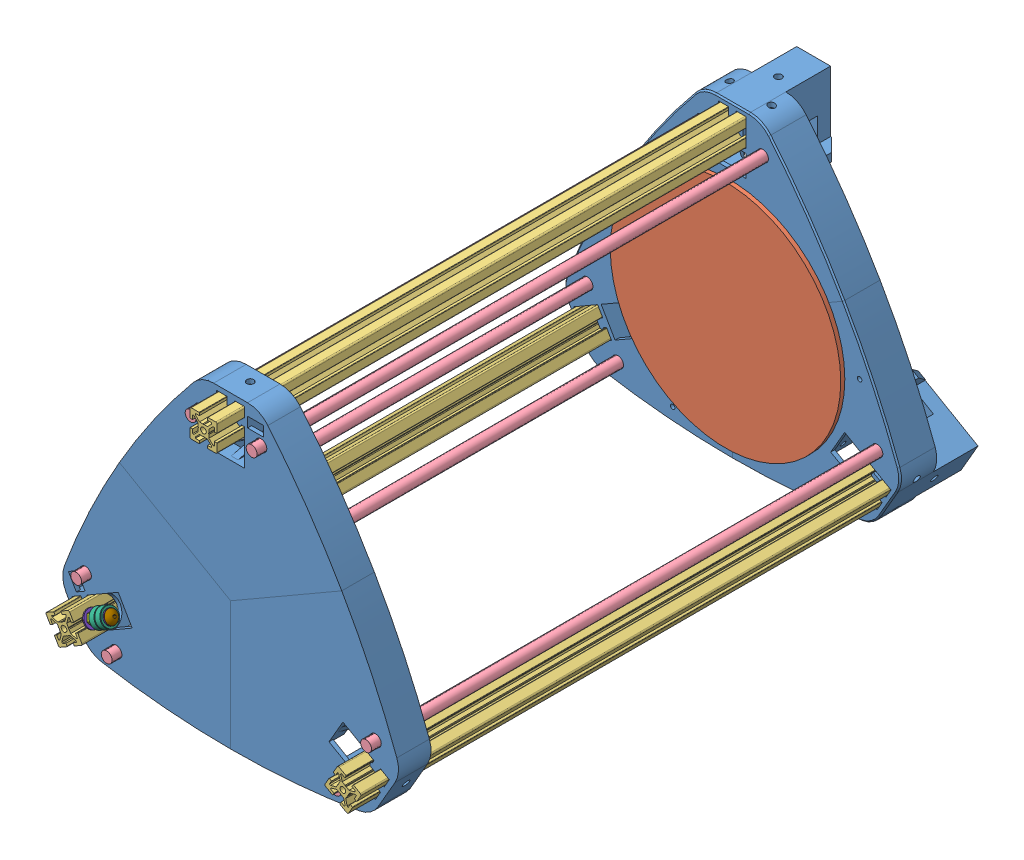
SolidWorks assembly 3DR Delta Printer, configuration Default. Lengths in mm.
Overall size (311.93 270.14 450).
32 component instances, 12 part files, 51 mates.
Components (placement in the parent):
- 3DR Bottom Motor Mount-1: 3DR Bottom Motor Mount [Default] at (103.057 -59.5 116.8875) x (-0.5 -0.866025 0) z (0 0 -1) size (164 132.75 60)
- 3DR Bottom Motor Mount-2: 3DR Bottom Motor Mount [Default] at (-103.057 -59.5 116.8875) x (-0.5 0.866025 0) z (0 0 -1) size (164 132.75 60)
- 3DR Bottom Motor Mount-3: 3DR Bottom Motor Mount [Default] at (0 119 116.8875) x (1 0 0) z (0 0 -1) size (164 132.75 60)
- Round Plate-1: Round Plate [Default] at (0 0 118.8875) size (170 170 3)
- HFSB5-2020-450-1: HFSB5-2020-450 [Default] at (102.8405 -59.375 506.8875) x (0.5 0.866025 0) z (0 0 1) size (20 20 450)
- HFSB5-2020-450-2: HFSB5-2020-450 [Default] at (0 118.75 506.8875) x (0 -1 0) z (0 0 1) size (20 20 450)
- HFSB5-2020-450-3: HFSB5-2020-450 [Default] at (-102.8405 -59.375 506.8875) x (-0.866025 -0.5 0) z (0 0 1) size (20 20 450)
- RGOCG8-400-1: RGOCG8-400 [Default] at (-84.4025 -74.7106 93.8875) x (-0.528567 -0.848892 0) z (0 0 1) size (8 8 400)
- RGOCG8-400-2: RGOCG8-400 [Default] at (-106.9025 -35.7394 93.8875) size (8 8 400)
- RGOCG8-400-3: RGOCG8-400 [Default] at (84.4025 -74.7106 93.8875) size (8 8 400)
- RGOCG8-400-4: RGOCG8-400 [Default] at (106.9025 -35.7394 93.8875) size (8 8 400)
- RGOCG8-400-5: RGOCG8-400 [Default] at (22.5 110.45 93.8875) size (8 8 400)
- RGOCG8-400-6: RGOCG8-400 [Default] at (-22.5 110.45 93.8875) size (8 8 400)
- 3DR_Spool_V2_001_RTP-1: 3DR_Spool_V2_001_RTP [Default] at (-97.0822 -43.3487 98.8875) x (0.5 -0.866025 0) z (0.866025 0.5 0) size (22 22 23) (hidden)
- Thread-1: Thread [Default] at (-87.4762 -40.1121 344.3217) x (0.866025 0.5 0) z (0 0 1) size (0.5 0.5 400) (hidden)
- Carriage for LM8UU-1: Carriage for LM8UU [Default] at (-93.0343 -53.7134 364.8923) x (-0.5 0.866025 0) z (0 0 -1) size (65.8 24.09 24)
- 3DR Bottom Motor Mount-4: 3DR Bottom Motor Mount [Top] at (-103.057 -59.5 486.8875) x (-0.5 0.866025 0) z (0 0 -1) size (164 132.75 25.42)
- 3DR Bottom Motor Mount-5: 3DR Bottom Motor Mount [Top] at (103.057 -59.5 486.8875) x (-0.5 -0.866025 0) z (0 0 -1) size (164 132.75 25.42)
- 3DR Bottom Motor Mount-6: 3DR Bottom Motor Mount [Top] at (0 119 486.8875) x (1 0 0) z (0 0 -1) size (164 132.75 25.42)
- Spectra Idler-1: Spectra Idler [Default] at (-89.2006 -51.5 495.0971) x (0 0 -1) z (0.866025 0.5 0) size (15.69 15.69 24.76)
  - 624ZZ-1: 624ZZ [Default] at origin size (13 13 5)
  - 624ZZ-2: 624ZZ [Default] at (0 0 5) size (13 13 5)
  - Nut-1: Nut [M5] at (0 0 -4.75) size (9.12 7.9 3.75)
  - Washer-1: Washer [M5] at (0 0 10) size (9.75 9.75 1)
  - Washer-2: Washer [M5] at (0 0 -1) size (9.75 9.75 1)
  - Washer-3: Washer [M5 Fender] at (0 0 -5.75) x (0.384822 -0.922991 0) z (0 0 1) size (12 12 1)
  - Button Head Screw-1: Button Head Screw [M5 x 22] at (0 0 -11) size (9.5 9.5 24.76)
- Spool and Screws-1: Spool and Screws [Default] at (-93.3142 -53.875 87.8875) x (0.136756 -0.236868 0.961869) z (0.866025 0.5 0) size (21.5 23.26 23)
  - Spool-1: Spool [Default] at origin size (21.5 23.26 23)
  - Button Head Screw-1: Button Head Screw [M3 x 6] at (-1.5 0 19.9458) x (0 0 1) z (-1 0 0) size (5.4 5.4 7.92)
  - Button Head Screw-2: Button Head Screw [M3 x 6] at (0.75 -1.299 19.9458) x (0 0 1) z (0.5 -0.866025 0) size (5.4 5.4 7.92)
  - Button Head Screw-3: Button Head Screw [M3 x 6] at (0.75 1.299 19.9458) x (0 0 1) z (0.5 0.866025 0) size (5.4 5.4 7.92)
Mates (geometry in assembly coordinates):
- Coincident10: coincident aligned: plane of Round Plate-1 through (0 0 118.8875) normal (0 1 0); plane of assembly through (0 0 0) normal (0 1 0)
- Coincident11: coincident aligned: plane of Round Plate-1 through (0 0 118.8875) normal (1 0 0); plane of assembly through (0 0 0) normal (1 0 0)
- Distance1: distance = 2 mm anti-aligned: plane of Round Plate-1 through (0 0 118.8875) normal (0 0 -1); plane of 3DR Bottom Motor Mount-3 through (-12.5 132.75 116.8875) normal (0 0 1)
- Coincident12: coincident anti-aligned: plane of 3DR Bottom Motor Mount-1 through (99.3053 -45.4982 56.8875) normal (0.866025 -0.5 0); plane of HFSB5-2020-450-1 through (98.6803 -46.5808 56.8875) normal (-0.866025 0.5 0)
- Width1: width anti-aligned: plane of HFSB5-2020-450-1 through (104.9826 -49.0647 56.8875) normal (0.5 0.866025 0); plane of HFSB5-2020-450-1 through (90.0463 -63.5353 56.8875) normal (-0.5 -0.866025 0); plane of 3DR Bottom Motor Mount-1 through (117.0588 -55.7482 56.8875) normal (-0.5 -0.866025 0); plane of 3DR Bottom Motor Mount-1 through (106.8088 -73.5018 56.8875) normal (0.5 0.866025 0)
- Coincident14: coincident aligned: plane of 3DR Bottom Motor Mount-1 through (121.2149 -55.5497 56.8875) normal (0 0 -1); plane of HFSB5-2020-450-1 through (90.5463 -62.6692 56.8875) normal (0 0 -1)
- Coincident15: coincident anti-aligned: plane of 3DR Bottom Motor Mount-3 through (-10.25 108.75 56.8875) normal (0 1 0); plane of HFSB5-2020-450-2 through (-9 108.75 56.8875) normal (0 -1 0)
- Width2: width anti-aligned: plane of 3DR Bottom Motor Mount-3 through (-10.25 129.25 56.8875) normal (1 0 0); plane of 3DR Bottom Motor Mount-3 through (10.25 129.25 56.8875) normal (-1 0 0); plane of HFSB5-2020-450-2 through (-10 115.45 56.8875) normal (-1 0 0); plane of HFSB5-2020-450-2 through (10 109.75 56.8875) normal (1 0 0)
- Coincident16: coincident aligned: plane of 3DR Bottom Motor Mount-3 through (-12.5 132.75 56.8875) normal (0 0 -1); plane of HFSB5-2020-450-2 through (9 127.75 56.8875) normal (0 0 -1)
- Coincident17: coincident anti-aligned: plane of 3DR Bottom Motor Mount-2 through (-89.0553 -63.2518 56.8875) normal (-0.866025 -0.5 0); plane of HFSB5-2020-450-3 through (-89.6803 -62.1692 56.8875) normal (0.866025 0.5 0)
- Width3: width anti-aligned: plane of 3DR Bottom Motor Mount-2 through (-106.8088 -73.5018 56.8875) normal (-0.5 0.866025 0); plane of 3DR Bottom Motor Mount-2 through (-117.0588 -55.7482 56.8875) normal (0.5 -0.866025 0); plane of HFSB5-2020-450-3 through (-94.9826 -66.3853 56.8875) normal (0.5 -0.866025 0); plane of HFSB5-2020-450-3 through (-100.0463 -46.2147 56.8875) normal (-0.5 0.866025 0)
- Coincident18: coincident aligned: plane of 3DR Bottom Motor Mount-2 through (-108.7149 -77.2003 56.8875) normal (0 0 -1); plane of HFSB5-2020-450-3 through (-90.5463 -62.6692 56.8875) normal (0 0 -1)
- Concentric1: concentric anti-aligned: cylinder of 3DR Bottom Motor Mount-2 through (-84.4025 -74.7106 93.8875) axis (0 0 1) radius 4.15; cylinder of RGOCG8-400-1 through (-84.4025 -74.7106 493.8875) axis (0 0 -1) radius 4
- Coincident19: coincident anti-aligned: plane of 3DR Bottom Motor Mount-2 through (-84.4025 -74.7106 93.8875) normal (0 0 1); plane of RGOCG8-400-1 through (-84.4025 -74.7106 93.8875) normal (0 0 -1)
- Coincident20: coincident aligned: plane of RGOCG8-400-1 through (-84.4025 -74.7106 93.8875) normal (0 0 1); plane of RGOCG8-400-2 through (-106.9025 -35.7394 93.8875) normal (0 0 1)
- Concentric2: concentric anti-aligned: cylinder of 3DR Bottom Motor Mount-2 through (-106.9025 -35.7394 93.8875) axis (0 0 1) radius 4.15; cylinder of RGOCG8-400-2 through (-106.9025 -35.7394 493.8875) axis (0 0 -1) radius 4
- Coincident21: coincident aligned: plane of RGOCG8-400-1 through (-84.4025 -74.7106 93.8875) normal (0 0 1); plane of RGOCG8-400-3 through (84.4025 -74.7106 93.8875) normal (0 0 1)
- Concentric3: concentric anti-aligned: cylinder of 3DR Bottom Motor Mount-1 through (84.4025 -74.7106 93.8875) axis (0 0 1) radius 4.15; cylinder of RGOCG8-400-3 through (84.4025 -74.7106 493.8875) axis (0 0 -1) radius 4
- Coincident22: coincident aligned: plane of RGOCG8-400-1 through (-84.4025 -74.7106 93.8875) normal (0 0 1); plane of RGOCG8-400-4 through (106.9025 -35.7394 93.8875) normal (0 0 1)
- Concentric4: concentric anti-aligned: cylinder of 3DR Bottom Motor Mount-1 through (106.9025 -35.7394 93.8875) axis (0 0 1) radius 4.15; cylinder of RGOCG8-400-4 through (106.9025 -35.7394 493.8875) axis (0 0 -1) radius 4
- Coincident23: coincident aligned: plane of RGOCG8-400-1 through (-84.4025 -74.7106 93.8875) normal (0 0 1); plane of RGOCG8-400-5 through (22.5 110.45 93.8875) normal (0 0 1)
- Concentric5: concentric anti-aligned: cylinder of 3DR Bottom Motor Mount-3 through (22.5 110.45 93.8875) axis (0 0 1) radius 4.15; cylinder of RGOCG8-400-5 through (22.5 110.45 493.8875) axis (0 0 -1) radius 4
- Coincident24: coincident aligned: plane of RGOCG8-400-1 through (-84.4025 -74.7106 93.8875) normal (0 0 1); plane of RGOCG8-400-6 through (-22.5 110.45 93.8875) normal (0 0 1)
- Concentric6: concentric anti-aligned: cylinder of 3DR Bottom Motor Mount-3 through (-22.5 110.45 93.8875) axis (0 0 1) radius 4.15; cylinder of RGOCG8-400-6 through (-22.5 110.45 493.8875) axis (0 0 -1) radius 4
- Concentric7: concentric aligned: cylinder of 3DR Bottom Motor Mount-2 through (-113.2434 -65.3811 87.8875) axis (0.866025 0.5 0) radius 14.5; line of 3DR_Spool_V2_001_RTP-1 through (-161.6436 -93.325 87.8875) axis (0.866025 0.5 0)
- Distance2: distance = 24 mm aligned: plane of 3DR_Spool_V2_001_RTP-1 through (-97.0822 -43.3487 98.8875) normal (0.866025 0.5 0); plane of 3DR Bottom Motor Mount-2 through (-59.2976 -60.7936 116.8875) normal (0.866025 0.5 0)
- Parallel1: parallel anti-aligned: plane of 3DR_Spool_V2_001_RTP-1; plane of assembly through (0 0 0) normal (0 0 1)
- Distance5: distance = 2 mm anti-aligned: plane of 3DR_Spool_V2_001_RTP-1; plane of Thread-1
- Concentric10: concentric anti-aligned: cylinder of RGOCG8-400-2 through (-106.9025 -35.7394 493.8875) axis (0 0 -1) radius 4; cylinder of Carriage for LM8UU-1 through (-106.9025 -35.7394 340.8923) axis (0 0 1) radius 7.9
- Concentric11: concentric anti-aligned: cylinder of RGOCG8-400-1 through (-84.4025 -74.7106 493.8875) axis (0 0 -1) radius 4; cylinder of Carriage for LM8UU-1 through (-84.4025 -74.7106 340.8923) axis (0 0 1) radius 7.9
- Concentric12: concentric anti-aligned: cylinder of RGOCG8-400-1 through (-84.4025 -74.7106 493.8875) axis (0 0 -1) radius 4; cylinder of 3DR Bottom Motor Mount-4 through (-84.4025 -74.7106 463.8875) axis (0 0 1) radius 4.25
- Concentric13: concentric anti-aligned: cylinder of RGOCG8-400-2 through (-106.9025 -35.7394 493.8875) axis (0 0 -1) radius 4; cylinder of 3DR Bottom Motor Mount-4 through (-106.9025 -35.7394 463.8875) axis (0 0 1) radius 4.25
- Distance6: distance = 20 mm aligned: plane of 3DR Bottom Motor Mount-4 through (-108.7149 -77.2003 486.8875) normal (0 0 1); plane of HFSB5-2020-450-3 through (-90.5463 -62.6692 506.8875) normal (0 0 1)
- Concentric14: concentric anti-aligned: cylinder of RGOCG8-400-4 through (106.9025 -35.7394 493.8875) axis (0 0 -1) radius 4; cylinder of 3DR Bottom Motor Mount-5 through (106.9025 -35.7394 463.8875) axis (0 0 1) radius 4.25
- Concentric15: concentric anti-aligned: cylinder of RGOCG8-400-3 through (84.4025 -74.7106 493.8875) axis (0 0 -1) radius 4; cylinder of 3DR Bottom Motor Mount-5 through (84.4025 -74.7106 463.8875) axis (0 0 1) radius 4.25
- Coincident26: coincident aligned: plane of 3DR Bottom Motor Mount-4 through (-108.7149 -77.2003 486.8875) normal (0 0 1); plane of 3DR Bottom Motor Mount-5 through (121.2149 -55.5497 486.8875) normal (0 0 1)
- Concentric17: concentric anti-aligned: cylinder of RGOCG8-400-5 through (22.5 110.45 493.8875) axis (0 0 -1) radius 4; cylinder of 3DR Bottom Motor Mount-6 through (22.5 110.45 463.8875) axis (0 0 1) radius 4.25
- Concentric18: concentric anti-aligned: cylinder of RGOCG8-400-6 through (-22.5 110.45 493.8875) axis (0 0 -1) radius 4; cylinder of 3DR Bottom Motor Mount-6 through (-22.5 110.45 463.8875) axis (0 0 1) radius 4.25
- Coincident27: coincident aligned: plane of 3DR Bottom Motor Mount-5 through (121.2149 -55.5497 486.8875) normal (0 0 1); plane of 3DR Bottom Motor Mount-6 through (-12.5 132.75 486.8875) normal (0 0 1)
- Concentric20: concentric anti-aligned: cylinder of 3DR Bottom Motor Mount-2 through (-113.2434 -65.3811 87.8875) axis (0.866025 0.5 0) radius 14.5; cylinder of Spool and Screws-1/Spool-1 through (-80.3239 -46.375 87.8875) axis (-0.866025 -0.5 0) radius 9
- Coincident28: coincident anti-aligned: plane of 3DR Bottom Motor Mount-2 through (-82 47.3427 113.8875) normal (0.5 0.866025 0); plane of 3DR Bottom Motor Mount-3 through (-82 47.3427 113.8875) normal (-0.5 -0.866025 0)
- Coincident29: coincident anti-aligned: plane of 3DR Bottom Motor Mount-1 through (0 -94.6854 113.8875) normal (-1 0 0); plane of 3DR Bottom Motor Mount-2 through (0 -94.6854 113.8875) normal (1 0 0)
- Coincident30: coincident anti-aligned: plane of 3DR Bottom Motor Mount-1 through (82 47.3427 113.8875) normal (-0.5 0.866025 0); plane of 3DR Bottom Motor Mount-3 through (82 47.3427 113.8875) normal (0.5 -0.866025 0)
- Coincident31: coincident: point of 3DR Bottom Motor Mount-1; line of 3DR Bottom Motor Mount-3 through (82 47.3427 89.8875) axis (0 0 1)
- Coincident32: coincident aligned: plane of 3DR Bottom Motor Mount-2 through (-91.8455 -67.4608 89.8875) normal (0 0 -1); plane of 3DR Bottom Motor Mount-3 through (-12.5 113.2709 89.8875) normal (0 0 -1)
- Coincident37: coincident: point of 3DR Bottom Motor Mount-1; point of 3DR Bottom Motor Mount-2
- Coincident38: coincident: point of 3DR Bottom Motor Mount-1; plane of assembly
- Coincident39: coincident: point of 3DR Bottom Motor Mount-1; plane of assembly
- Distance8: distance = 1 mm anti-aligned: plane of Spool and Screws-1/Spool-1 through (-93.3142 -53.875 87.8875) normal (-0.866025 -0.5 0); plane of 3DR Bottom Motor Mount-2 through (-89.0553 -63.2518 56.8875) normal (0.866025 0.5 0)
- Coincident41: coincident anti-aligned: plane of HFSB5-2020-450-3 through (-89.6803 -62.1692 56.8875) normal (0.866025 0.5 0); plane of Spectra Idler-1/Washer-3 through (-94.1803 -54.375 495.0971) normal (-0.866025 -0.5 0)
- Coincident42: coincident anti-aligned: plane of HFSB5-2020-450-3; plane of Spectra Idler-1/624ZZ-1
